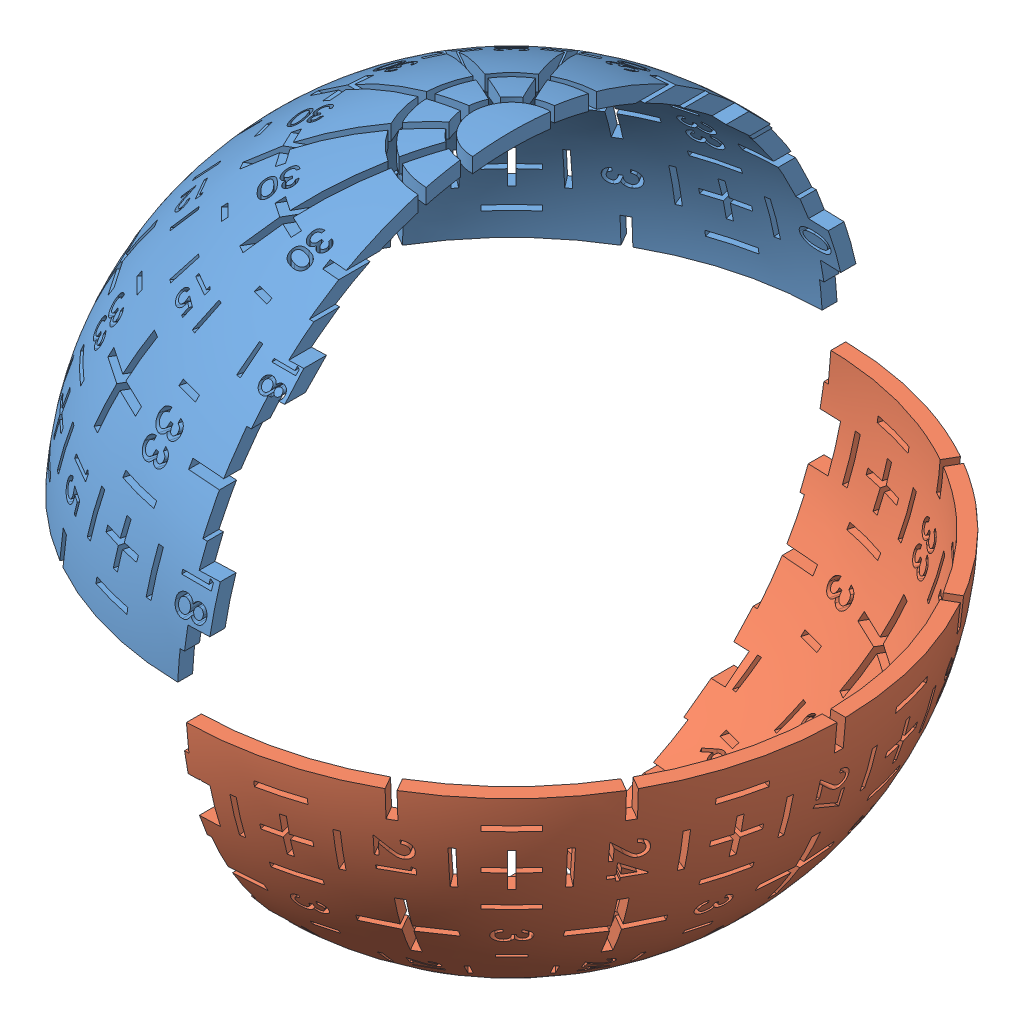
SolidWorks assembly WhiteColored_Balls, configuration Default. Lengths in mm.
Overall size (113.06 88.9 112.94).
2 component instances, 2 part files, 2 mates.
Components (placement in the parent):
- WhiteBallV2_TopColored-1: WhiteBallV2_TopColored [Default] at (-21.5448 -32.4159 17.5791) size (88.9 88.9 88.79)
- WhiteBallV2_BottomColored-1: WhiteBallV2_BottomColored [Default] at (-21.5448 -32.3159 17.5791) x (0.5 0 -0.866025) z (-0.866025 0 -0.5) size (82.56 88.9 82.89)
Mates (geometry in assembly coordinates):
- Concentric1: concentric: circle of WhiteBallV2_TopColored-1; circle of WhiteBallV2_BottomColored-1
- Distance2: distance = 4.1 mm: plane of WhiteBallV2_BottomColored-1 through (-21.5448 -34.4159 17.5791) normal (0 1 0); plane of WhiteBallV2_TopColored-1 through (-21.5448 -30.3159 17.5791) normal (0 -1 0)
